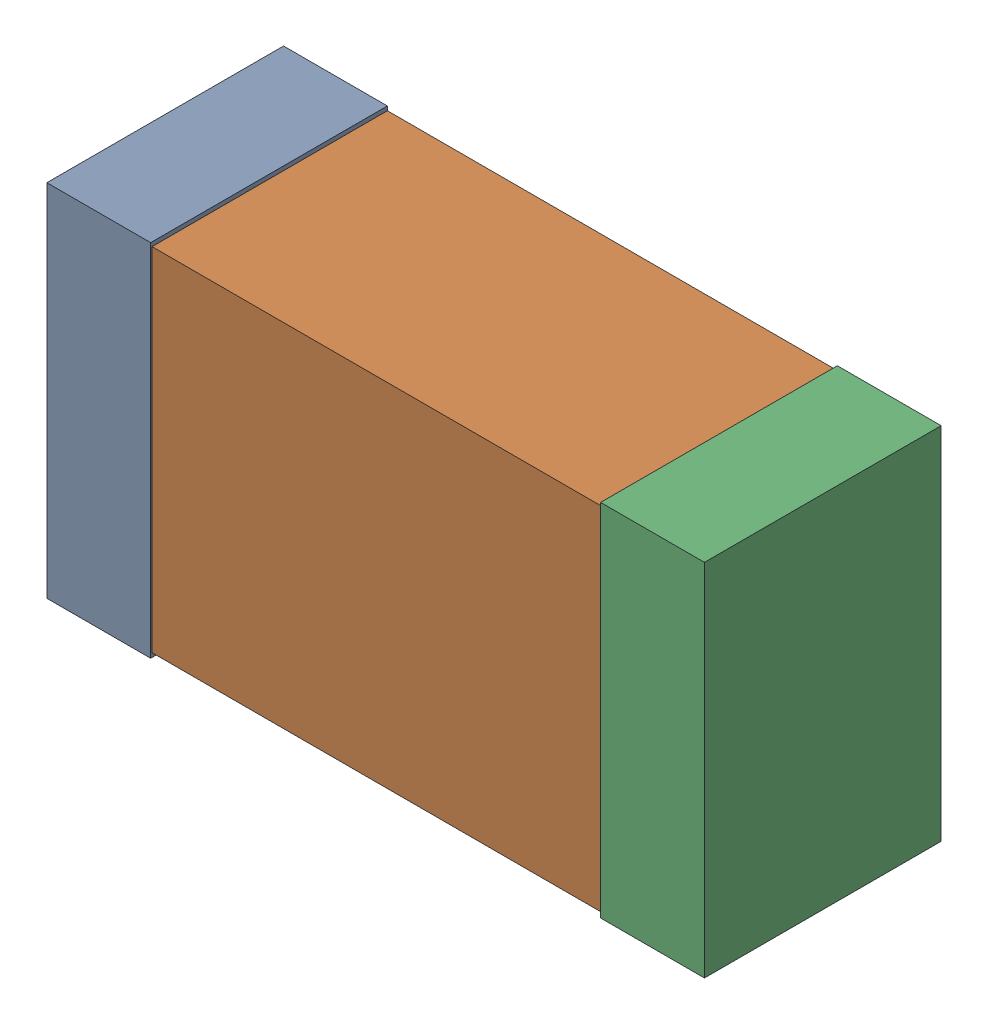
SolidWorks assembly R3_Motor_11Kanaloa_v2.0.0_Motor, configuration Default. Lengths in mm.
Overall size (2.38 1.3 0.85).
6 component instances, 2 part files, 0 mates.
Components (placement in the parent):
- 352877648-1: 352877648 [Default] at (127.016 175.768 0) size (0.38 1.3 0.85)
  - Extruded_14-1: Extruded_14 [Default] at origin size (0.38 1.3 0.85)
- 352877392-1: 352877392 [Default] at (128.016 175.768 0) size (2.2 1.27 0.85)
  - Extruded_15-1: Extruded_15 [Default] at origin size (2.2 1.27 0.85)
- 352877648-2: 352877648 [Default] at (129.016 175.768 0) size (0.38 1.3 0.85)
  - Extruded_14-1: Extruded_14 [Default] at origin size (0.38 1.3 0.85)
